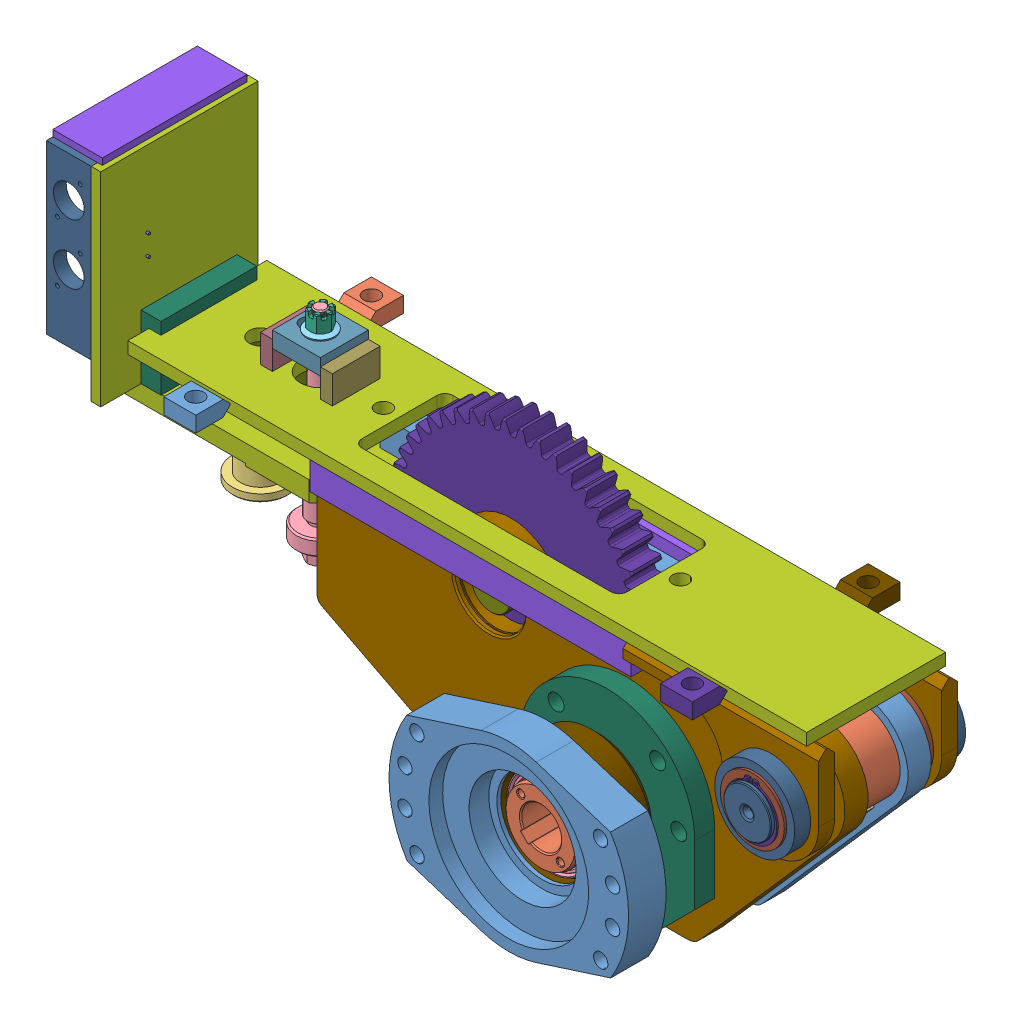
SolidWorks assembly g1_3_1_1, configuration 默认. Lengths in mm.
Overall size (943 530 331.8).
109 component instances, 72 part files, 46 mates.
Components (placement in the parent):
- g1_3_1_1_5_1-1: g1_3_1_1_5_1 [默认] at (310.2802 -95 30) x (-1 0 0) z (0 1 0) size (926 108 318.6)
  - g1_3_1_1_5-1_af1_1-1: g1_3_1_1_5-1_af1_1 [默认] at origin size (661 29 318.6)
  - g1_3_1_1_5-2_af0_1-1: g1_3_1_1_5-2_af0_1 [默认] at (-213.2 29 0) size (100 50 100)
  - g1_3_1_1_5-4_1-1: g1_3_1_1_5-4_1 [默认] at (-149.9151 54 -132.7301) x (0 1 0) z (-0.659692 0 0.751536) size (50 10 223)
  - g1_3_1_1_5-5_1-1: g1_3_1_1_5-5_1 [默认] at (20.5 54 -217) x (1 0 0) z (0 1 0) size (194 10 50)
  - g1_3_1_1_5-6_1-1: g1_3_1_1_5-6_1 [默认] at (248.4498 54 -161.5242) x (0 1 0) z (0.890083 0 0.455798) size (50 10 284)
  - g1_3_1_1_5-7_1-1: g1_3_1_1_5-7_1 [默认] at (377.8 54 -43.9) x (0 0 -1) z (0 1 0) size (87 10 50)
  - g1_3_1_1_5-9_af0_1-1: g1_3_1_1_5-9_af0_1 [默认] at (502.8 54 24.6) x (1 0 0) z (0 1 0) size (300 25 108)
  - g1_3_1_1_5-8_1-1: g1_3_1_1_5-8_1 [默认] at (437.8 54 49.6) x (1 0 0) z (0 1 0) size (60 50 60)
  - g1_3_1_1_5-1_af0_1-1: g1_3_1_1_5-1_af0_1 [默认] at (0 79 0) size (661 29 318.6)
- g1_3_1_1_4_1-1: g1_3_1_1_4_1 [默认] at (523.4802 -95 -33.3) x (1 0 0) z (0 -1 0) size (80 234 80)
  - g1_3_1_1_4-1_1-1: g1_3_1_1_4-1_1 [默认] at origin size (60 234 60.04)
  - g1_3_1_1_4-3_1-2: g1_3_1_1_4-3_1 [默认] at (0 224.3 0) size (80 3 80)
  - g1_3_1_1_4-2_1-1: g1_3_1_1_4-2_1 [默认] at (0 174.3 0) size (72 50 72)
  - g1_3_1_1_4-2_1-2: g1_3_1_1_4-2_1 [默认] at (0 9.7 0) size (72 50 72)
  - g1_3_1_1_4-2_1-3: g1_3_1_1_4-2_1 [默认] at (0 62.7 0) size (72 50 72)
  - g1_3_1_1_4-2_1-4: g1_3_1_1_4-2_1 [默认] at (0 121.3 0) size (72 50 72)
- g1_3_1_1_2_1-1: g1_3_1_1_2_1 [默认] at (310.2802 -195.4 0) x (0.999998 0.002137 0) z (0.002137 -0.999998 0) size (219.6 152 245)
  - g1_3_1_1_2-1_1-1: g1_3_1_1_2-1_1 [默认] at origin size (219.6 61 245)
  - g1_3_1_1_2-2_1-1: g1_3_1_1_2-2_1 [默认] at (0 152 0) x (-0.047609 0 0.998866) z (0 1 0) size (120.16 120.16 117)
  - g1_3_1_1_2-3_1-1: g1_3_1_1_2-3_1 [默认] at (-20.1525 129 20.1525) x (0 -1 0) z (0.707107 0 0.707107) size (28 11 14)
- g1_3_1_1_3_1-1: g1_3_1_1_3_1 [默认] at (137.4802 -78.4 83.75) x (0 0 -1) z (-0.004458 0.99999 0) size (103.5 321.87 322.01)
  - g1_3_1_1_3-1_1-1: g1_3_1_1_3-1_1 [默认] at origin size (103.5 52 52)
  - _X2_60F08F6E_X0_g1_3_1_1_3-2_1-1: _X2_60F08F6E_X0_g1_3_1_1_3-2_1 [默认] at (25 0 0) x (0 0 1) z (1 0 0) size (322.01 321.87 50.08)
- g1_3_1_1_1_2-1: g1_3_1_1_1_2 [默认] at (310.2802 -195.4 123.8) x (0.999998 0.002137 0) z (0.002137 -0.999998 0) size (300 165.8 228)
  - g1_3_1_1_1_1_1-1: g1_3_1_1_1_1_1 [默认] at origin size (300 112 228)
    - g1_3_1_1_1_1-2_af0_1-1: g1_3_1_1_1_1-2_af0_1 [默认] at (0 50 0) size (150 65 150)
    - g1_3_1_1_1_1-3_af0_1-1: g1_3_1_1_1_1-3_af0_1 [默认] at (0 140 0) size (300 47 228)
  - g1_3_1_1_1-2_1-1: g1_3_1_1_1-2_1 [默认] at (0 122.2 0) x (0.707107 0 0.707107) z (0.707107 0 -0.707107) size (90 126 90)
  - g1_3_1_1_1-1_1-1: g1_3_1_1_1-1_1 [默认] at (0 77 0) x (0 1 0) z (0 0 1) size (20 110 110)
  - b90x110x12_gb9877_1_1-1: b90x110x12_gb9877_1_1 [默认] at (0 66.9 0) size (108.6 17.9 108.6)
    - b90x110x12_gb9877_1_rubber_1-1: b90x110x12_gb9877_1_rubber_1 [默认] at origin size (108.6 12 108.6)
    - b90x110x12_gb9877_1_frame_1-1: b90x110x12_gb9877_1_frame_1 [默认] at (0 -2.4 0) x (-1 0 0) z (0 0 1) size (107.2 9.5 107.2)
  - b90x110x12_gb9877_1_1-2: b90x110x12_gb9877_1_1 [默认] at (0 104.8 0) size (108.6 17.9 108.6)
    - b90x110x12_gb9877_1_rubber_1-1: b90x110x12_gb9877_1_rubber_1 [默认] at origin size (108.6 12 108.6)
    - b90x110x12_gb9877_1_frame_1-1: b90x110x12_gb9877_1_frame_1 [默认] at (0 -2.4 0) x (-1 0 0) z (0 0 1) size (107.2 9.5 107.2)
  - 80_gb894_1_1-1: 80_gb894_1_1 [默认] at (-2.4 11.1 -38.1746) x (1 0 0) z (0 -1 0) size (85.83 90.87 2.5)
- g1_3_1_1_6_1-1: g1_3_1_1_6_1 [默认] at (137.4802 0 84) x (-1 0 0) z (0 0 1) size (875 200 260)
  - g1_3_1_1_6-4_af0_1-1: g1_3_1_1_6-4_af0_1 [默认] at origin size (850 15 174)
  - g1_3_1_1_6-8_1-1: g1_3_1_1_6-8_1 [默认] at (0 40 57) x (1 0 0) z (0 -1 0) size (402 20 44.8)
  - g1_3_1_1_6-8_1-2: g1_3_1_1_6-8_1 [默认] at (0 40 -77) x (1 0 0) z (0 -1 0) size (402 20 44.8)
  - g1_3_1_1_6-1_1-1: g1_3_1_1_6-1_1 [默认] at (-386 95 -87) x (1 0 0) z (0 -1 0) size (245 20 140)
  - g1_3_1_1_6-1_1-2: g1_3_1_1_6-1_1 [默认] at (-386 95 67) x (1 0 0) z (0 -1 0) size (245 20 140)
  - g1_3_1_1_6-3_1-1: g1_3_1_1_6-3_1 [默认] at (-386 95 87) x (-1 0 0) z (0 1 0) size (100 20 100)
  - g1_3_1_1_6-3_1-2: g1_3_1_1_6-3_1 [默认] at (-386 95 -107) x (-1 0 0) z (0 1 0) size (100 20 100)
  - g1_3_1_1_6-2_1-1: g1_3_1_1_6-2_1 [默认] at (-386 95 57) x (-1 0 0) z (0 1 0) size (100 10 100)
  - g1_3_1_1_6-2_1-2: g1_3_1_1_6-2_1 [默认] at (-386 95 -57) x (1 0 0) z (0 1 0) size (100 10 100)
  - g1_3_1_1_6-9_1-1: g1_3_1_1_6-9_1 [默认] at (220 -17 0) x (0 1 0) z (0 0 -1) size (35 15 60)
  - g1_3_1_1_6-9_af0_1-1: g1_3_1_1_6-9_af0_1 [默认] at (310 -17 0) x (0 1 0) z (0 0 1) size (35 15 60)
  - g1_3_1_1_6-10_1-1: g1_3_1_1_6-10_1 [默认] at (265 -45 0) size (60 20 60)
  - g1_3_1_1_6-12_af0_1-1: g1_3_1_1_6-12_af0_1 [默认] at (434 25 0.5) x (0 0 1) z (0 -1 0) size (120 25 80)
  - g1_3_1_1_6-11_af0_1-1: g1_3_1_1_6-11_af0_1 [默认] at (357 15 0) size (94 40 60)
  - g1_3_1_1_6-5_af0_1-1: g1_3_1_1_6-5_af0_1 [默认] at (-311 -5 108.5) x (0 0 -1) z (1 0 0) size (43 19.6 40)
  - g1_3_1_1_6-5_af1_1-1: g1_3_1_1_6-5_af1_1 [默认] at (-311 -5 -108.5) x (0 0 1) z (-1 0 0) size (43 19.6 40)
  - g1_3_1_1_6-5_af2_1-1: g1_3_1_1_6-5_af2_1 [默认] at (311 -5 108.5) x (0 0 -1) z (1 0 0) size (43 19.6 40)
  - g1_3_1_1_6-5_af3_1-1: g1_3_1_1_6-5_af3_1 [默认] at (311 -5 -108.5) x (0 0 1) z (-1 0 0) size (43 19.6 40)
- g1_3_1_1-1_1-1: g1_3_1_1-1_1 [默认] at (-202.5198 -45.5 84) x (1 0 -0.00083) z (-0.00083 0 -1) size (70 135 70)
- g1_3_1_1_7_1-1: g1_3_1_1_7_1 [默认] at (-127.5198 -16.0167 84) x (0 1 0) z (0.020278 0 0.999794) size (272.02 60 60)
  - g1_3_1_1_7-1_1-1: g1_3_1_1_7-1_1 [默认] at origin size (272.02 60 60)
  - a35_5_gb1972_1-1: a35_5_gb1972_1 [默认] at (39.2167 0 0) x (0 0.075145 0.997173) z (0 0.997173 -0.075145) size (35.5 7.2 35.5)
  - a35_5_gb1972_1-2: a35_5_gb1972_1 [默认] at (62.8167 0 0) x (0 -0.99777 0.066751) z (0 -0.066751 -0.99777) size (35.5 7.2 35.5)
  - m16a_gb6178_1-1: m16a_gb6178_1 [默认] at (85.8167 13.8564 0) x (0 -1 0) z (-1 0 0) size (27.71 24 20.8)
- g1_3_1_1_8_1-1: g1_3_1_1_8_1 [默认] at (-291.5198 62.5 96.5) x (0 0 -1) z (0 1 0) size (197 71 268.3)
  - g1_3_1_1_8_1_af0_1-1: g1_3_1_1_8_1_af0_1 [默认] at origin size (197 68 263)
    - g1_3_1_1_8_1-3_af1_1-1: g1_3_1_1_8_1-3_af1_1 [默认] at origin size (197 12 255)
    - g1_3_1_1_8_1-1_1-1: g1_3_1_1_8_1-1_1 [默认] at (0 37 127.5) x (1 0 0) z (0 -1 0) size (181 8 62)
    - g1_3_1_1_8_1-2_af1_1-1: g1_3_1_1_8_1-2_af1_1 [默认] at (98.5 40 22.5) x (0 1 0) z (0 0 1) size (56 16 210)
    - g1_3_1_1_8_1-2_af0_1-1: g1_3_1_1_8_1-2_af0_1 [默认] at (-98.5 40 22.5) x (0 1 0) z (0 0 -1) size (56 16 210)
    - g1_3_1_1_8_1-5_1-1: g1_3_1_1_8_1-5_1 [默认] at (0 40 -82.5) x (1 0 0) z (0 1 0) size (165 8 56)
    - g1_3_1_1_8_1-6_1-1: g1_3_1_1_8_1-6_1 [默认] at (27.5 40 -106) x (0 1 0) z (0 0 -1) size (56 6 31)
    - g1_3_1_1_8_1-6_1-2: g1_3_1_1_8_1-6_1 [默认] at (-8.5 40 -106) x (0 1 0) z (0 0 -1) size (56 6 31)
    - g1_3_1_1_8_1-4_af1_1-1: g1_3_1_1_8_1-4_af1_1 [默认] at (-10 12 5) size (105 17 85)
    - g1_3_1_1_8_1-8_af0_1-1: g1_3_1_1_8_1-8_af0_1 [默认] at (12.5 40 -127.5) x (0 1 0) z (1 0 0) size (56 6 54)
  - g1_3_1_1_8-3_1-1: g1_3_1_1_8-3_1 [默认] at (12.5 37 -32.7987) x (0 0 -1) z (0 1 0) size (229 15 15)
  - g1_3_1_1_8-6_1-1: g1_3_1_1_8-6_1 [默认] at (12.5 37 30.1) x (-1 0 0) z (0 1 0) size (26 60 26)
  - g1_3_1_1_8-5_1-1: g1_3_1_1_8-5_1 [默认] at (12.5 29 -27.5) size (60 24 20)
  - g1_3_1_1_8-9_af0_1-1: g1_3_1_1_8-9_af0_1 [默认] at (-42.5 17 5.5) size (34 10 74)
  - g1_3_1_1_8-10_1-1: g1_3_1_1_8-10_1 [默认] at (12.5 37 -127.5) x (1 0 0) z (0 1 0) size (40 2 32)
  - ya2x20x90-2_gb2089_af0_1-1: ya2x20x90-2_gb2089_af0_1 [默认] at (12.5 37 -82.5) x (0 0 -1) z (1 0 0) size (92.3 24.62 24.71)
  - 14x2_65_gb3452_1_1-1: 14x2_65_gb3452_1_1 [默认] at (12.5 37 -124.5) x (0 0 1) z (0 1 0) size (2.65 19.38 19.38)
  - 15_gb894_1_1-1: 15_gb894_1_1 [默认] at (12 29.8675 -73.9) size (17.18 18.67 1.11)
  - 15_gb894_1_1-2: 15_gb894_1_1 [默认] at (12 29.8675 29) size (17.18 18.67 1.11)
  - 8_gb93_1-1: 8_gb93_1 [默认] at (32.5 53 -27.5) x (-1 0 0) z (0 1 0) size (12.3 12.3 2.1)
  - m8x40_gb5782_1-1: m8x40_gb5782_1 [默认] at (32.5 55.1 -27.5) size (15.01 45.3 13)
  - 8_gb93_1-2: 8_gb93_1 [默认] at (-7.5 53 -27.5) x (-1 0 0) z (0 1 0) size (12.3 12.3 2.1)
  - m8x40_gb5782_1-2: m8x40_gb5782_1 [默认] at (-7.5 55.1 -27.5) size (15.01 45.3 13)
  - m3x10_gb818_1-1: m3x10_gb818_1 [默认] at (57.5 2 60.5) size (5.81 12.5 5.77)
  - m3x10_gb818_1-2: m3x10_gb818_1 [默认] at (57.5 2 100.5) size (5.81 12.5 5.77)
  - m3x10_gb818_1-3: m3x10_gb818_1 [默认] at (-17.5 2 100.5) size (5.81 12.5 5.77)
  - m3x10_gb818_1-4: m3x10_gb818_1 [默认] at (-57.5 2 100.5) size (5.81 12.5 5.77)
  - m3x30_gb818_1-1: m3x30_gb818_1 [默认] at (-40.5 -3 7.5) size (5.81 32.5 5.77)
  - m3x30_gb818_1-2: m3x30_gb818_1 [默认] at (-40.5 -3 32.9) size (5.81 32.5 5.77)
  - 6_gb93_1-9: 6_gb93_1 [默认] at (-52.5 28.6 -17.5) x (1 0 0) z (0 -1 0) size (9.3 9.3 1.6)
  - m6x20_gb5783_1-9: m6x20_gb5783_1 [默认] at (-52.5 28.6 -17.5) size (11.55 24 10)
  - 6_gb93_1-10: 6_gb93_1 [默认] at (-32.5 28.6 -17.5) x (1 0 0) z (0 -1 0) size (9.3 9.3 1.6)
  - m6x20_gb5783_1-10: m6x20_gb5783_1 [默认] at (-32.5 28.6 -17.5) size (11.55 24 10)
  - 5x14_gb119_2_1-1: 5x14_gb119_2_1 [默认] at (-42.5 27 -3.5) size (5 14 5)
  - m3x6_gb818_1-1: m3x6_gb818_1 [默认] at (27.5 37 -123.5) x (1 0 0) z (0 1 0) size (5.81 8.5 5.77)
  - m3x6_gb818_1-2: m3x6_gb818_1 [默认] at (-2.5 37 -123.5) x (1 0 0) z (0 1 0) size (5.81 8.5 5.77)
- _X2_57AB5708_X0_16_gb93_1-9: _X2_57AB5708_X0_16_gb93_1 [默认] at (-303.5198 -50 44) x (0 0.924225 0.381849) z (-1 0 0) size (24.4 24.4 4.1)
- _X2_87BA6813_X0_m16x35_gb5783_10_1-1: _X2_87BA6813_X0_m16x35_gb5783_10_1 [默认] at (-307.6198 -50 44) x (0 -0.866025 -0.5) z (0 0.5 -0.866025) size (27.71 45 24)
- _X2_57AB5708_X0_16_gb93_1-10: _X2_57AB5708_X0_16_gb93_1 [默认] at (-303.5198 -50 124) x (0 0.924225 0.381849) z (-1 0 0) size (24.4 24.4 4.1)
- _X2_87BA6813_X0_m16x35_gb5783_10_1-2: _X2_87BA6813_X0_m16x35_gb5783_10_1 [默认] at (-307.6198 -50 124) x (0 -0.866025 -0.5) z (0 0.5 -0.866025) size (27.71 45 24)
- g1_3_1_1_1_1-1_af0_1-1: g1_3_1_1_1_1-1_af0_1 [默认] at (310.2802 -195.4 113) x (1 0 0) z (0 -1 0) size (220 42 245)
- g1_3_1_1_7-2_1-1: g1_3_1_1_7-2_1 [默认] at (-159.2741 -95.4 83.9778) x (1 0 0.0007) z (0 -1 0) size (63.51 55 25)
- g1_3_1_1_4-3_1-2: g1_3_1_1_4-3_1 [默认] at (523.4802 -95 -23.6) x (-0.923728 -0.383049 0) z (0.383049 -0.923728 0) size (80 3 80)
- 60_gb894_1_1-2: 60_gb894_1_1 [默认] at (525.4302 -66.5668 -28.6) x (-1 0 0) z (0 0 1) size (65.16 69.76 2)
- 60_gb894_1_1-3: 60_gb894_1_1 [默认] at (525.4302 -66.5668 194) x (-1 0 0) z (0 0 1) size (65.16 69.76 2)
- 16x10x45_gb1096_1-2: 16x10x45_gb1096_1 [默认] at (137.3687 -53.4002 83.25) x (0 0 -1) z (0.004458 -0.99999 0) size (45 16 10)
Mates (geometry in assembly coordinates):
- 重合1: coincident anti-aligned: plane of g1_3_1_1_2_1-1/g1_3_1_1_2-3_1-1 through (285.2105 -210.6564 129) normal (-0.708616 0.705594 0); plane of g1_3_1_1_1_2-1/g1_3_1_1_1-2_1-1 through (284.9988 -210.869 246) normal (0.708616 -0.705594 0)
- 重合2: coincident anti-aligned: plane of g1_3_1_1_2_1-1/g1_3_1_1_2-2_1-1 through (310.2802 -195.4 120) normal (0 0 1); plane of g1_3_1_1_1_2-1/g1_3_1_1_1-2_1-1 through (310.2802 -195.4 120) normal (0 0 -1)
- 同心3: concentric aligned: cylinder of g1_3_1_1_2_1-1/g1_3_1_1_2-2_1-1 through (310.2802 -195.4 29.15) axis (0 0 1) radius 25; cylinder of g1_3_1_1_1_2-1/g1_3_1_1_1-2_1-1 through (310.2802 -195.4 246) axis (0 0 1) radius 25
- 同心9: concentric anti-aligned: cylinder of g1_3_1_1_8_1-1/g1_3_1_1_8_1_af0_1-1/g1_3_1_1_8_1-3_af1_1-1 through (-303.5198 -50 124) axis (1 0 0) radius 8.5; cylinder of _X2_87BA6813_X0_m16x35_gb5783_10_1-2 through (-270.8698 -50 124) axis (-1 0 0) radius 8
- 同心12: concentric anti-aligned: cylinder of g1_3_1_1_6_1-1/g1_3_1_1_6-12_af0_1-1 through (-248.0035 -50 44) axis (1 0 0) radius 7; cylinder of _X2_87BA6813_X0_m16x35_gb5783_10_1-1 through (-270.8698 -50 44) axis (-1 0 0) radius 8
- 同心13: concentric aligned: cylinder of _X2_57AB5708_X0_16_gb93_1-10 through (-303.5198 -50 124) axis (-1 0 0) radius 8.1; cylinder of _X2_87BA6813_X0_m16x35_gb5783_10_1-2 through (-270.8698 -50 124) axis (-1 0 0) radius 8
- 同心14: concentric aligned: cylinder of _X2_57AB5708_X0_16_gb93_1-9 through (-303.5198 -50 44) axis (-1 0 0) radius 8.1; cylinder of _X2_87BA6813_X0_m16x35_gb5783_10_1-1 through (-270.8698 -50 44) axis (-1 0 0) radius 8
- 重合3: coincident anti-aligned: plane of _X2_57AB5708_X0_16_gb93_1-9 through (-307.6198 -50 44) normal (-1 0 0); plane of _X2_87BA6813_X0_m16x35_gb5783_10_1-1 through (-307.6198 -50 44) normal (1 0 0)
- 重合4: coincident anti-aligned: plane of _X2_57AB5708_X0_16_gb93_1-10 through (-307.6198 -50 124) normal (-1 0 0); plane of _X2_87BA6813_X0_m16x35_gb5783_10_1-2 through (-307.6198 -50 124) normal (1 0 0)
- 同心15: concentric aligned: cylinder of g1_3_1_1_8_1-1/g1_3_1_1_8_1_af0_1-1/g1_3_1_1_8_1-3_af1_1-1 through (-303.5198 -50 44) axis (-1 0 0) radius 8.5; cylinder of _X2_87BA6813_X0_m16x35_gb5783_10_1-1 through (-270.8698 -50 44) axis (-1 0 0) radius 8
- 同心18: concentric aligned: cylinder of g1_3_1_1_6_1-1/g1_3_1_1_6-11_af0_1-1 through (-202.5198 71.0063 84) axis (0 -1 0) radius 14; cylinder of g1_3_1_1-1_1-1 through (-202.5198 -19.25 84) axis (0 -1 0) radius 15
- 同心20: concentric anti-aligned: cylinder of g1_3_1_1_5_1-1/g1_3_1_1_5-9_af0_1-1 through (-202.5198 -95.4 84) axis (0 1 0) radius 27; cylinder of g1_3_1_1-1_1-1 through (-202.5198 -50.5 84) axis (0 -1 0) radius 25
- 重合10: coincident anti-aligned: plane of g1_3_1_1_8_1-1/g1_3_1_1_8_1_af0_1-1/g1_3_1_1_8_1-3_af1_1-1 through (-303.5198 62.5 96.5) normal (-1 0 0); plane of _X2_57AB5708_X0_16_gb93_1-9 through (-303.5198 -50 44) normal (1 0 0)
- 重合12: coincident anti-aligned: plane of g1_3_1_1_8_1-1/g1_3_1_1_8_1_af0_1-1/g1_3_1_1_8_1-3_af1_1-1 through (-303.5198 62.5 96.5) normal (-1 0 0); plane of _X2_57AB5708_X0_16_gb93_1-10 through (-303.5198 -50 124) normal (1 0 0)
- 重合13: coincident anti-aligned: plane of g1_3_1_1_6_1-1/g1_3_1_1_6-12_af0_1-1 through (-291.5198 0 84) normal (-1 0 0); plane of g1_3_1_1_8_1-1/g1_3_1_1_8_1_af0_1-1/g1_3_1_1_8_1-3_af1_1-1 through (-291.5198 62.5 96.5) normal (1 0 0)
- 同心23: concentric aligned: cylinder of g1_3_1_1_5_1-1/g1_3_1_1_5-1_af1_1-1 through (523.4802 -95 30) axis (0 0 1) radius 36; cylinder of g1_3_1_1_6_1-1/g1_3_1_1_6-3_1-2 through (523.4802 -95 -23) axis (0 0 1) radius 36
- 同心24: concentric aligned: cylinder of g1_3_1_1_4_1-1/g1_3_1_1_4-2_1-2 through (523.4802 -95 -23.6) axis (0 0 1) radius 36; cylinder of g1_3_1_1_6_1-1/g1_3_1_1_6-3_1-2 through (523.4802 -95 -23) axis (0 0 1) radius 36
- 重合14: coincident anti-aligned: plane of g1_3_1_1_4_1-1/g1_3_1_1_4-3_1-2 through (523.4802 -95 191) normal (0 0 -1); plane of g1_3_1_1_6_1-1/g1_3_1_1_6-3_1-1 through (523.4802 -95 191) normal (0 0 1)
- 同心25: concentric aligned: cylinder of g1_3_1_1_5_1-1/g1_3_1_1_5-1_af1_1-1 through (137.4802 -78.4 30) axis (0 0 1) radius 45; cylinder of g1_3_1_1_3_1-1/g1_3_1_1_3-1_1-1 through (137.4802 -78.4 26.825) axis (0 0 1) radius 25
- 同心26: concentric aligned: cylinder of g1_3_1_1_5_1-1/g1_3_1_1_5-1_af1_1-1 through (310.2802 -195.4 30) axis (0 0 1) radius 75; cylinder of g1_3_1_1_2_1-1/g1_3_1_1_2-1_1-1 through (310.2802 -195.4 30) axis (0 0 1) radius 75
- 重合16: coincident anti-aligned: plane of g1_3_1_1_5_1-1/g1_3_1_1_5-1_af1_1-1 through (310.2802 -95 30) normal (0 0 -1); plane of g1_3_1_1_2_1-1/g1_3_1_1_2-1_1-1 through (310.2802 -195.4 30) normal (0 0 1)
- 重合17: coincident anti-aligned: plane of g1_3_1_1_5_1-1/g1_3_1_1_5-1_af1_1-1; plane of ? through (523.5275 -270.9624 278.2595) normal (0 -1 0)
- 重合19: coincident aligned: plane of g1_3_1_1_5_1-1/g1_3_1_1_5-1_af0_1-1 through (137.4802 -78.4 128.8) normal (0 0 1); plane of g1_3_1_1_3_1-1/g1_3_1_1_3-1_1-1 through (137.4802 -78.4 128.8) normal (0 0 1)
- 重合28: coincident anti-aligned: plane of g1_3_1_1_2_1-1/g1_3_1_1_2-1_1-1 through (310.2802 -195.4 0) normal (0 0 -1); plane of assembly through (0 0 0) normal (0 0 1)
- 重合31: coincident aligned: plane of g1_3_1_1_6_1-1/g1_3_1_1_6-4_af0_1-1 through (137.4802 0 84) normal (0 1 0); plane of assembly through (0 0 0) normal (0 1 0)
- 同心28: concentric aligned: cylinder of g1_3_1_1_6_1-1/g1_3_1_1_6-12_af0_1-1 through (-248.0035 -50 124) axis (-1 0 0) radius 7; cylinder of _X2_87BA6813_X0_m16x35_gb5783_10_1-2 through (-270.8698 -50 124) axis (-1 0 0) radius 8
- 同心29: concentric aligned: cylinder of g1_3_1_1_5_1-1/g1_3_1_1_5-1_af0_1-1 through (310.2802 -195.4 109) axis (0 0 1) radius 75; cylinder of g1_3_1_1_1_1-1_af0_1-1 through (310.2802 -195.4 -384.4109) axis (0 0 1) radius 75
- 同心30: concentric aligned: cylinder of g1_3_1_1_5_1-1/g1_3_1_1_5-1_af0_1-1 through (246.6802 -131.8 108.5324) axis (0 0 1) radius 5.1; cylinder of g1_3_1_1_1_1-1_af0_1-1 through (246.6802 -131.8 163) axis (0 0 1) radius 10
- 重合33: coincident anti-aligned: plane of g1_3_1_1_5_1-1/g1_3_1_1_5-1_af0_1-1 through (310.2802 -95 138) normal (0 0 1); plane of g1_3_1_1_1_1-1_af0_1-1 through (310.2802 -195.4 138) normal (0 0 -1)
- 平行2: parallel aligned: plane of ? through (593.4401 -66.5668 194.2) normal (1 0 0); plane of g1_3_1_1_6_1-1/g1_3_1_1_6-1_1-2 through (655.3901 -95 151) normal (1 0 0)
- 重合37: coincident anti-aligned: plane of g1_3_1_1_6_1-1/g1_3_1_1_6-11_af0_1-1 through (-172.5198 -50.5 114) normal (0 -1 0); plane of g1_3_1_1-1_1-1 through (-202.5198 -50.5 84) normal (0 1 0)
- 平行5: parallel anti-aligned: plane of g1_3_1_1_8_1-1/g1_3_1_1_8_1_af0_1-1/g1_3_1_1_8_1-5_1-1 through (-331.5198 -28 96.5) normal (0 -1 0); plane of _X2_87BA6813_X0_m16x35_gb5783_10_1-2 through (-307.6198 -38 130.9282) normal (0 1 0)
- 平行6: parallel anti-aligned: plane of g1_3_1_1_8_1-1/g1_3_1_1_8_1_af0_1-1/g1_3_1_1_8_1-5_1-1 through (-331.5198 -28 96.5) normal (0 -1 0); plane of _X2_87BA6813_X0_m16x35_gb5783_10_1-1 through (-307.6198 -38 50.9282) normal (0 1 0)
- 同心33: concentric anti-aligned: cylinder of g1_3_1_1_6_1-1/g1_3_1_1_6-10_1-1 through (-127.5198 45 84) axis (0 -1 0) radius 10; cylinder of g1_3_1_1_7_1-1/g1_3_1_1_7-1_1-1 through (-127.5198 -471.3188 84) axis (0 1 0) radius 8.9
- 同心34: concentric anti-aligned: cylinder of g1_3_1_1_7_1-1/g1_3_1_1_7-1_1-1 through (-127.5198 -471.3188 84) axis (0 1 0) radius 16; cylinder of g1_3_1_1_7-2_1-1 through (-127.5198 -95.4 84) axis (0 -1 0) radius 16.376
- 重合38: coincident anti-aligned: plane of g1_3_1_1_5_1-1/g1_3_1_1_5-8_1-1 through (-127.5198 -95.4 84) normal (0 -1 0); plane of g1_3_1_1_7-2_1-1 through (-159.2741 -95.4 83.9778) normal (0 1 0)
- 距离1: distance = 4 mm anti-aligned: plane of g1_3_1_1_7_1-1/g1_3_1_1_7-1_1-1 through (-127.5198 21 84) normal (0 1 0); plane of g1_3_1_1_6_1-1/g1_3_1_1_6-10_1-1 through (-127.5198 25 84) normal (0 -1 0)
- 重合40: coincident anti-aligned: plane of g1_3_1_1_4_1-1/g1_3_1_1_4-2_1-2 through (523.4802 -95 -23.6) normal (0 0 -1); plane of g1_3_1_1_4-3_1-2 through (523.4802 -95 -23.6) normal (0 0 1)
- 同心35: concentric anti-aligned: cylinder of g1_3_1_1_4_1-1/g1_3_1_1_4-1_1-1 through (523.4802 -95 -33.3) axis (0 0 1) radius 30; cylinder of g1_3_1_1_4-3_1-2 through (523.4802 -95 -23.6) axis (0 0 -1) radius 30.5
- 同心36: concentric aligned: cylinder of g1_3_1_1_4_1-1/g1_3_1_1_4-1_1-1 through (523.4802 -95 450.0941) axis (0 0 1) radius 28.5; cylinder of 60_gb894_1_1-2 through (523.4802 -95 -28.6) axis (0 0 1) radius 28.5
- 重合41: coincident anti-aligned: plane of g1_3_1_1_4-3_1-2 through (523.4802 -95 -26.6) normal (0 0 -1); plane of 60_gb894_1_1-2 through (525.4302 -66.5668 -26.6) normal (0 0 1)
- 重合42: coincident anti-aligned: plane of g1_3_1_1_4_1-1/g1_3_1_1_4-3_1-2 through (523.4802 -95 194) normal (0 0 1); plane of 60_gb894_1_1-3 through (525.4302 -66.5668 194) normal (0 0 -1)
- 同心37: concentric aligned: cylinder of g1_3_1_1_4_1-1/g1_3_1_1_4-1_1-1 through (523.4802 -95 -282.6941) axis (0 0 1) radius 28.5; cylinder of 60_gb894_1_1-3 through (523.4802 -95 194) axis (0 0 1) radius 28.5
- 重合51: coincident anti-aligned: plane of g1_3_1_1_3_1-1/g1_3_1_1_3-1_1-1 through (137.391 -58.4002 83.75) normal (-0.004458 0.99999 0); plane of 16x10x45_gb1096_1-2 through (137.391 -58.4002 83.25) normal (0.004458 -0.99999 0)
- 同心39: concentric aligned: cylinder of g1_3_1_1_3_1-1/g1_3_1_1_3-1_1-1 through (137.3643 -52.4003 68.75) axis (-0.004458 0.99999 0) radius 8; cylinder of 16x10x45_gb1096_1-2 through (137.3911 -58.4158 68.75) axis (-0.004458 0.99999 0) radius 8
- 重合52: coincident anti-aligned: plane of g1_3_1_1_3_1-1/g1_3_1_1_3-1_1-1 through (145.3642 -52.3646 98.75) normal (-0.99999 -0.004458 0); plane of 16x10x45_gb1096_1-2 through (145.3464 -48.3646 60.75) normal (0.99999 0.004458 0)
